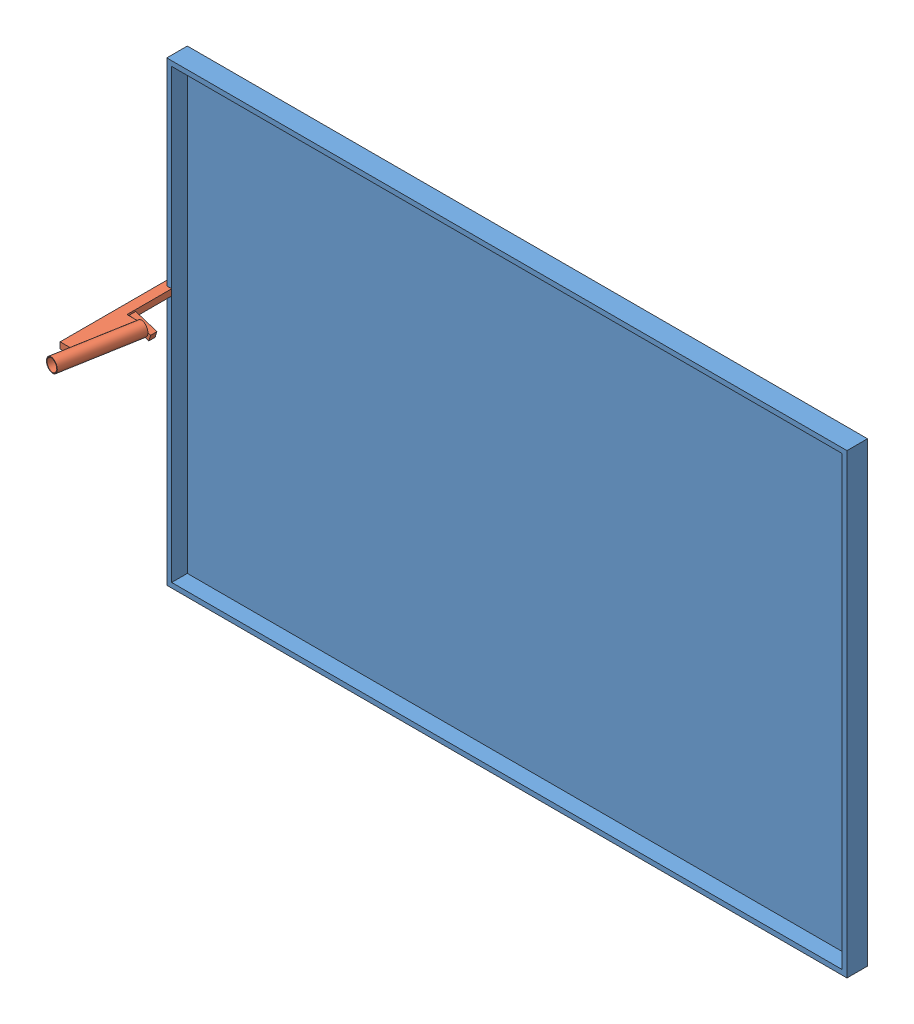
SolidWorks assembly Table2018, configuration Default. Lengths in mm.
Overall size (3066 2044 647.1).
2 component instances, 2 part files, 2 mates.
Components (placement in the parent):
- Table2018Support-1: Table2018Support [Default] at (705.949 1579.8301 2523.4987) size (3044 2044 92)
- BallDistributor-1: BallDistributor [Default] at (-838.051 1704.0356 2545.4987) x (1 0 0) z (0 -1 0) size (150.15 625.1 69.68)
Mates (geometry in assembly coordinates):
- Coïncidente1: coincident: plane of Table2018Support-1 through (-816.051 2601.8301 2615.4987) normal (-1 0 0); plane of BallDistributor-1 through (-816.051 1632.1303 2341.2778) normal (1 0 0)
- Coïncidente2: coincident anti-aligned: plane of Table2018Support-1 through (705.949 1579.8301 2615.4987) normal (0 0 1); plane of BallDistributor-1 through (-816.051 1690.0356 2615.4987) normal (0 0 -1)
